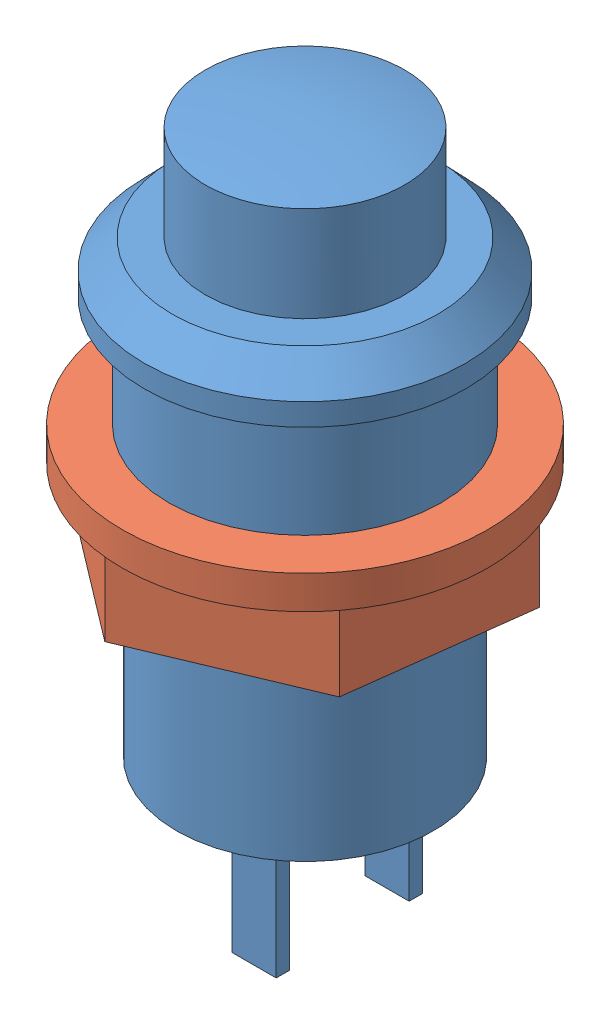
SolidWorks assembly ButtonAssem, configuration По умолчанию. Lengths in mm.
Overall size (18.44 31.1 18.44).
2 component instances, 2 part files, 3 mates.
Components (placement in the parent):
- Button-1: Button [По умолчанию] at origin size (14.5 31.1 14.5)
- ButtonNut-1: ButtonNut [По умолчанию] at (0 -5 0) x (0.992066 0 0.125721) z (-0.125721 0 0.992066) size (16.5 5 16.5)
Mates (geometry in assembly coordinates):
- Coincident1: coordinate: point of Button1-1
- Concentric1: concentric anti-aligned: cylinder of Button1-1 through (0 17.9633 0) axis (0 1 0) radius 6.15; cylinder of Button12-1 through (0 -8.4966 0) axis (0 -1 0) radius 6
- Coincident2: coincident aligned: plane of Button1-1 through (-6.15 -10 0) normal (0 -1 0); plane of Button12-1 through (-8.1845 -10 -1.0372) normal (0 -1 0)
